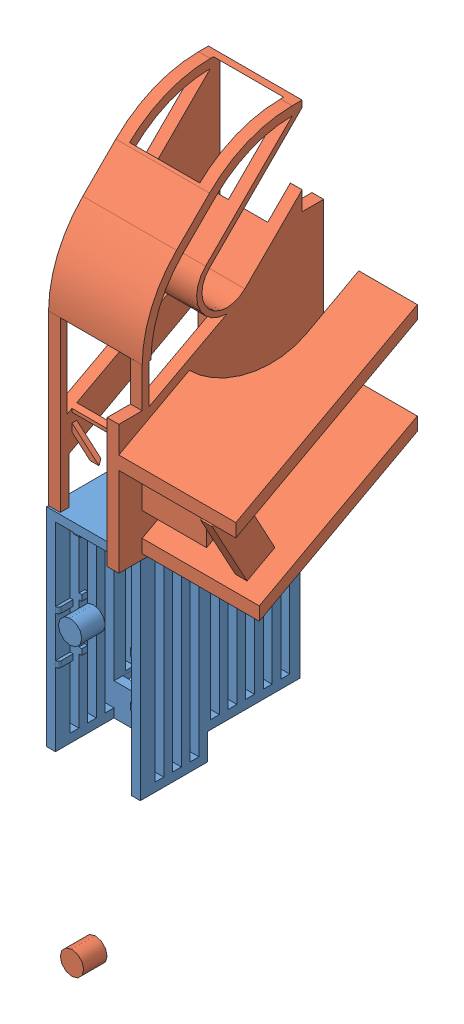
SolidWorks assembly Assem1, configuration Default. Lengths in mm.
Overall size (36 101.5 35.23).
2 component instances, 2 part files, 3 mates.
Components (placement in the parent):
- Reach back-1: Reach back [Default] at (8.7772 8.6868 11.5713) size (16 37.5 31.32)
- Reach front-1: Reach front [Default] at (8.7772 -40.4636 11.2526) size (36 118 35.23)
Mates (geometry in assembly coordinates):
- Coincident1: coincident: plane of Reach back-1 through (116.7772 40.1868 51.5925) normal (0 1 0); plane of Reach front-1 through (-78.6223 40.1868 56.3797) normal (0 -1 0)
- Coincident2: coincident: point of Reach back-1; point of Reach front-1
- Parallel1: parallel aligned: plane of Reach back-1 through (-1.0707 42.6868 13.2526) normal (0 0 -1); plane of Reach front-1 through (-0.0959 160.0364 12.9339) normal (0 0 -1)
